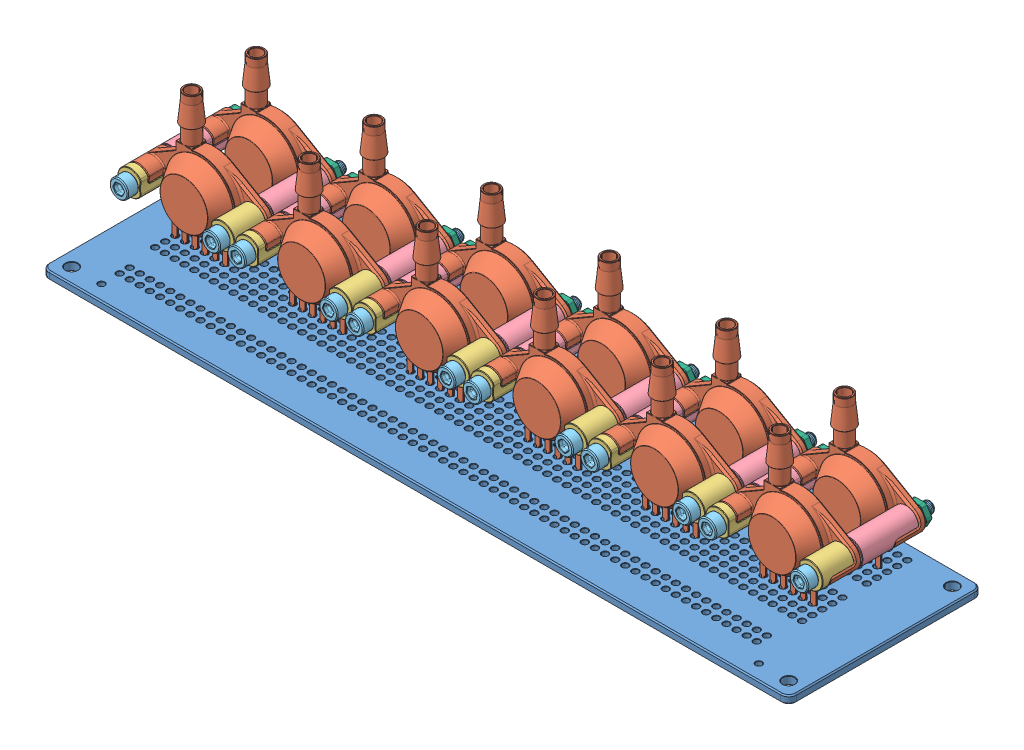
SolidWorks assembly AARL_Puppy_18_03_02_000, configuration Default. Lengths in mm.
Overall size (187.96 37.75 48.78).
61 component instances, 6 part files, 168 mates.
Components (placement in the parent):
- AARL_Puppy_18_03_01_006-1: AARL_Puppy_18_03_01_006 [Default] at origin size (187.96 2 48.78)
- AARL_Puppy_18_03_01_002-MPX5700GP-1: AARL_Puppy_18_03_01_002-MPX5700GP [Default] at (-77.5527 13 4.34) size (29.5 37.75 8.49)
- AARL_Puppy_18_03_01_002-MPX5700GP-2: AARL_Puppy_18_03_01_002-MPX5700GP [Default] at (-47.9676 13 4.34) size (29.5 37.75 8.49)
- AARL_Puppy_18_03_01_002-MPX5700GP-3: AARL_Puppy_18_03_01_002-MPX5700GP [Default] at (-18.3825 13 4.34) size (29.5 37.75 8.49)
- AARL_Puppy_18_03_01_002-MPX5700GP-4: AARL_Puppy_18_03_01_002-MPX5700GP [Default] at (11.2026 13 4.34) size (29.5 37.75 8.49)
- AARL_Puppy_18_03_01_002-MPX5700GP-5: AARL_Puppy_18_03_01_002-MPX5700GP [Default] at (40.7877 13 4.34) size (29.5 37.75 8.49)
- AARL_Puppy_18_03_01_002-MPX5700GP-6: AARL_Puppy_18_03_01_002-MPX5700GP [Default] at (70.3728 13 4.34) size (29.5 37.75 8.49)
- AARL_Puppy_18_03_01_002-MPX5700GP-7: AARL_Puppy_18_03_01_002-MPX5700GP [Default] at (-77.5527 13 -11.94) size (29.5 37.75 8.49)
- AARL_Puppy_18_03_01_002-MPX5700GP-8: AARL_Puppy_18_03_01_002-MPX5700GP [Default] at (-47.9676 13 -11.94) size (29.5 37.75 8.49)
- AARL_Puppy_18_03_01_002-MPX5700GP-9: AARL_Puppy_18_03_01_002-MPX5700GP [Default] at (-18.3825 13 -11.94) size (29.5 37.75 8.49)
- AARL_Puppy_18_03_01_002-MPX5700GP-10: AARL_Puppy_18_03_01_002-MPX5700GP [Default] at (11.2026 13 -11.94) size (29.5 37.75 8.49)
- AARL_Puppy_18_03_01_002-MPX5700GP-11: AARL_Puppy_18_03_01_002-MPX5700GP [Default] at (40.7877 13 -11.94) size (29.5 37.75 8.49)
- AARL_Puppy_18_03_01_002-MPX5700GP-12: AARL_Puppy_18_03_01_002-MPX5700GP [Default] at (70.3728 13 -11.94) size (29.5 37.75 8.49)
- AARL_Puppy_18_03_01_007-1: AARL_Puppy_18_03_01_007 [Default] at (-89.1077 13 14.3385) x (0 1 0) z (-1 0 0) size (6.35 8 5.84)
- AARL_Puppy_18_03_01_007-2: AARL_Puppy_18_03_01_007 [Default] at (-65.9977 13 14.3385) x (0 -1 0) z (1 0 0) size (6.35 8 5.84)
- AARL_Puppy_18_03_01_007-3: AARL_Puppy_18_03_01_007 [Default] at (-59.5226 13 14.3385) x (0 1 0) z (-1 0 0) size (6.35 8 5.84)
- AARL_Puppy_18_03_01_007-4: AARL_Puppy_18_03_01_007 [Default] at (-36.4126 13 14.3385) x (0 -1 0) z (1 0 0) size (6.35 8 5.84)
- AARL_Puppy_18_03_01_007-5: AARL_Puppy_18_03_01_007 [Default] at (-29.9375 13 14.3385) x (0 1 0) z (-1 0 0) size (6.35 8 5.84)
- AARL_Puppy_18_03_01_007-6: AARL_Puppy_18_03_01_007 [Default] at (-6.8275 13 14.3385) x (0 -1 0) z (1 0 0) size (6.35 8 5.84)
- AARL_Puppy_18_03_01_007-7: AARL_Puppy_18_03_01_007 [Default] at (-0.3524 13 14.3385) x (0 1 0) z (-1 0 0) size (6.35 8 5.84)
- AARL_Puppy_18_03_01_007-8: AARL_Puppy_18_03_01_007 [Default] at (22.7576 13 14.3385) x (0 -1 0) z (1 0 0) size (6.35 8 5.84)
- AARL_Puppy_18_03_01_007-9: AARL_Puppy_18_03_01_007 [Default] at (29.2327 13 14.3385) x (0 1 0) z (-1 0 0) size (6.35 8 5.84)
- AARL_Puppy_18_03_01_007-10: AARL_Puppy_18_03_01_007 [Default] at (52.3427 13 14.3385) x (0 -1 0) z (1 0 0) size (6.35 8 5.84)
- AARL_Puppy_18_03_01_007-11: AARL_Puppy_18_03_01_007 [Default] at (58.8178 13 14.3385) x (0 1 0) z (-1 0 0) size (6.35 8 5.84)
- AARL_Puppy_18_03_01_007-12: AARL_Puppy_18_03_01_007 [Default] at (81.9278 13 14.3385) x (0 -1 0) z (1 0 0) size (6.35 8 5.84)
- AARL_Puppy_18_03_01_008-1: AARL_Puppy_18_03_01_008 [Default] at (-89.1077 13 4.3399) x (0 1 0) z (-1 0 0) size (6.35 14.28 5.84)
- AARL_Puppy_18_03_01_008-2: AARL_Puppy_18_03_01_008 [Default] at (-65.9977 13 4.3399) x (0 -1 0) z (1 0 0) size (6.35 14.28 5.84)
- AARL_Puppy_18_03_01_008-3: AARL_Puppy_18_03_01_008 [Default] at (-59.5226 13 4.3399) x (0 1 0) z (-1 0 0) size (6.35 14.28 5.84)
- AARL_Puppy_18_03_01_008-4: AARL_Puppy_18_03_01_008 [Default] at (-36.4126 13 4.3399) x (0 -1 0) z (1 0 0) size (6.35 14.28 5.84)
- AARL_Puppy_18_03_01_008-5: AARL_Puppy_18_03_01_008 [Default] at (-29.9375 13 4.3399) x (0 1 0) z (-1 0 0) size (6.35 14.28 5.84)
- AARL_Puppy_18_03_01_008-6: AARL_Puppy_18_03_01_008 [Default] at (-6.8275 13 4.3399) x (0 -1 0) z (1 0 0) size (6.35 14.28 5.84)
- AARL_Puppy_18_03_01_008-7: AARL_Puppy_18_03_01_008 [Default] at (-0.3524 13 4.3399) x (0 1 0) z (-1 0 0) size (6.35 14.28 5.84)
- AARL_Puppy_18_03_01_008-8: AARL_Puppy_18_03_01_008 [Default] at (22.7576 13 4.3399) x (0 -1 0) z (1 0 0) size (6.35 14.28 5.84)
- AARL_Puppy_18_03_01_008-9: AARL_Puppy_18_03_01_008 [Default] at (29.2327 13 4.3399) x (0 1 0) z (-1 0 0) size (6.35 14.28 5.84)
- AARL_Puppy_18_03_01_008-10: AARL_Puppy_18_03_01_008 [Default] at (52.3427 13 4.3399) x (0 -1 0) z (1 0 0) size (6.35 14.28 5.84)
- AARL_Puppy_18_03_01_008-11: AARL_Puppy_18_03_01_008 [Default] at (58.8178 13 4.3399) x (0 1 0) z (-1 0 0) size (6.35 14.28 5.84)
- AARL_Puppy_18_03_01_008-12: AARL_Puppy_18_03_01_008 [Default] at (81.9278 13 4.3399) x (0 -1 0) z (1 0 0) size (6.35 14.28 5.84)
- AARL_Puppy_18_04_01_010-1: AARL_Puppy_18_04_01_010 [Default] at (-89.1077 13 17.1833) x (0.827068 0.562102 0) z (-0.562102 0.827068 0) size (4.65 33.19 4.65)
- AARL_Puppy_18_04_01_010-2: AARL_Puppy_18_04_01_010 [Default] at (-65.9977 13 17.1833) x (0.827068 0.562102 0) z (-0.562102 0.827068 0) size (4.65 33.19 4.65)
- AARL_Puppy_18_04_01_010-3: AARL_Puppy_18_04_01_010 [Default] at (-59.5226 13 17.1833) x (0.567888 -0.823106 0) z (0.823106 0.567888 0) size (4.65 33.19 4.65)
- AARL_Puppy_18_04_01_010-4: AARL_Puppy_18_04_01_010 [Default] at (-36.4126 13 17.1833) x (0.934298 -0.356493 0) z (0.356493 0.934298 0) size (4.65 33.19 4.65)
- AARL_Puppy_18_04_01_010-5: AARL_Puppy_18_04_01_010 [Default] at (-29.9375 13 17.1833) x (0.934298 -0.356493 0) z (0.356493 0.934298 0) size (4.65 33.19 4.65)
- AARL_Puppy_18_04_01_010-6: AARL_Puppy_18_04_01_010 [Default] at (-6.8275 13 17.1833) x (0.934298 -0.356493 0) z (0.356493 0.934298 0) size (4.65 33.19 4.65)
- AARL_Puppy_18_04_01_010-7: AARL_Puppy_18_04_01_010 [Default] at (-0.3524 13 17.1833) x (0.422012 -0.90659 0) z (0.90659 0.422012 0) size (4.65 33.19 4.65)
- AARL_Puppy_18_04_01_010-8: AARL_Puppy_18_04_01_010 [Default] at (22.7576 13 17.1833) x (0.687558 -0.726129 0) z (0.726129 0.687558 0) size (4.65 33.19 4.65)
- AARL_Puppy_18_04_01_010-9: AARL_Puppy_18_04_01_010 [Default] at (29.2327 13 17.1833) x (-0.114467 -0.993427 0) z (0.993427 -0.114467 0) size (4.65 33.19 4.65)
- AARL_Puppy_18_04_01_010-10: AARL_Puppy_18_04_01_010 [Default] at (52.3427 13 17.1833) x (-0.114467 -0.993427 0) z (0.993427 -0.114467 0) size (4.65 33.19 4.65)
- AARL_Puppy_18_04_01_010-11: AARL_Puppy_18_04_01_010 [Default] at (58.8178 13 17.1833) x (-0.684268 -0.729231 0) z (0.729231 -0.684268 0) size (4.65 33.19 4.65)
- AARL_Puppy_18_04_01_010-12: AARL_Puppy_18_04_01_010 [Default] at (81.9278 13 17.1833) x (-0.684268 -0.729231 0) z (0.729231 -0.684268 0) size (4.65 33.19 4.65)
- AARL_Puppy_18_04_07_002-1: AARL_Puppy_18_04_07_002 [Default] at (-89.1077 13 -12.7338) x (1 0 0) z (0 -1 0) size (5.77 1.59 5.21)
- AARL_Puppy_18_04_07_002-2: AARL_Puppy_18_04_07_002 [Default] at (-65.9977 13 -12.7338) x (1 0 0) z (0 -1 0) size (5.77 1.59 5.21)
- AARL_Puppy_18_04_07_002-3: AARL_Puppy_18_04_07_002 [Default] at (-59.5226 13 -12.7338) x (1 0 0) z (0 -1 0) size (5.77 1.59 5.21)
- AARL_Puppy_18_04_07_002-4: AARL_Puppy_18_04_07_002 [Default] at (-36.4126 13 -12.7338) x (1 0 0) z (0 -1 0) size (5.77 1.59 5.21)
- AARL_Puppy_18_04_07_002-5: AARL_Puppy_18_04_07_002 [Default] at (-29.9375 13 -12.7338) x (1 0 0) z (0 -1 0) size (5.77 1.59 5.21)
- AARL_Puppy_18_04_07_002-6: AARL_Puppy_18_04_07_002 [Default] at (-6.8275 13 -12.7338) x (1 0 0) z (0 -1 0) size (5.77 1.59 5.21)
- AARL_Puppy_18_04_07_002-7: AARL_Puppy_18_04_07_002 [Default] at (-0.3524 13 -12.7338) x (0.513984 -0.8578 0) z (-0.8578 -0.513984 0) size (5.77 1.59 5.21)
- AARL_Puppy_18_04_07_002-8: AARL_Puppy_18_04_07_002 [Default] at (22.7576 13 -12.7338) x (0.513984 -0.8578 0) z (-0.8578 -0.513984 0) size (5.77 1.59 5.21)
- AARL_Puppy_18_04_07_002-9: AARL_Puppy_18_04_07_002 [Default] at (29.2327 13 -12.7338) x (0.513984 -0.8578 0) z (-0.8578 -0.513984 0) size (5.77 1.59 5.21)
- AARL_Puppy_18_04_07_002-10: AARL_Puppy_18_04_07_002 [Default] at (52.3427 13 -12.7338) x (0.513984 -0.8578 0) z (-0.8578 -0.513984 0) size (5.77 1.59 5.21)
- AARL_Puppy_18_04_07_002-11: AARL_Puppy_18_04_07_002 [Default] at (58.8178 13 -12.7338) x (0.513984 -0.8578 0) z (-0.8578 -0.513984 0) size (5.77 1.59 5.21)
- AARL_Puppy_18_04_07_002-12: AARL_Puppy_18_04_07_002 [Default] at (81.9278 13 -12.7338) x (0.513984 -0.8578 0) z (-0.8578 -0.513984 0) size (5.77 1.59 5.21)
Mates (geometry in assembly coordinates):
- Width1: width: plane of AARL_Puppy_18_03_01_002-MPX5700GP-1 through (-83.5277 -4.75 7.94) normal (1 0 0); plane of AARL_Puppy_18_03_01_002-MPX5700GP-1 through (-84.2777 -4.75 7.94) normal (-1 0 0); cylinder of AARL_Puppy_18_03_01_006-1 through (-83.9027 -1 8.14) axis (0 1 0) radius 0.75
- Width2: width: plane of AARL_Puppy_18_03_01_002-MPX5700GP-1 through (-89.1077 13 8.34) normal (0 0 1); plane of AARL_Puppy_18_03_01_002-MPX5700GP-1 through (-83.1527 33.001 7.94) normal (0 0 -1); cylinder of AARL_Puppy_18_03_01_006-1 through (-83.9027 -1 8.14) axis (0 1 0) radius 0.75
- Width3: width: plane of AARL_Puppy_18_03_01_002-MPX5700GP-1 through (-89.1077 13 8.34) normal (0 0 1); plane of AARL_Puppy_18_03_01_002-MPX5700GP-1 through (-70.4527 33.001 7.94) normal (0 0 -1); cylinder of AARL_Puppy_18_03_01_006-1 through (-71.5756 -1 8.14) axis (0 1 0) radius 0.75
- Coincident1: coincident anti-aligned: plane of AARL_Puppy_18_03_01_006-1 through (0 1 0) normal (0 1 0); plane of AARL_Puppy_18_03_01_002-MPX5700GP-1 through (-77.5527 1 4.34) normal (0 -1 0)
- Width4: width: plane of AARL_Puppy_18_03_01_002-MPX5700GP-2 through (-59.5226 13 8.34) normal (0 0 1); plane of AARL_Puppy_18_03_01_002-MPX5700GP-2 through (-53.5676 33.001 7.94) normal (0 0 -1); cylinder of AARL_Puppy_18_03_01_006-1 through (-54.3176 -1 8.14) axis (0 1 0) radius 0.75
- Width5: width: plane of AARL_Puppy_18_03_01_002-MPX5700GP-2 through (-40.8676 33.001 7.94) normal (0 0 -1); plane of AARL_Puppy_18_03_01_002-MPX5700GP-2 through (-59.5226 13 8.34) normal (0 0 1); cylinder of AARL_Puppy_18_03_01_006-1 through (-41.9905 -1 8.14) axis (0 1 0) radius 0.75
- Width6: width: plane of AARL_Puppy_18_03_01_002-MPX5700GP-2 through (-54.6926 -4.75 7.94) normal (-1 0 0); plane of AARL_Puppy_18_03_01_002-MPX5700GP-2 through (-53.9426 -4.75 7.94) normal (1 0 0); cylinder of AARL_Puppy_18_03_01_006-1 through (-54.3176 -1 8.14) axis (0 1 0) radius 0.75
- Coincident2: coincident anti-aligned: plane of AARL_Puppy_18_03_01_006-1 through (0 1 0) normal (0 1 0); plane of AARL_Puppy_18_03_01_002-MPX5700GP-2 through (-47.9676 1 4.34) normal (0 -1 0)
- Width7: width: plane of AARL_Puppy_18_03_01_002-MPX5700GP-3 through (-23.9825 33.001 7.94) normal (0 0 -1); plane of AARL_Puppy_18_03_01_002-MPX5700GP-3 through (-29.9375 13 8.34) normal (0 0 1); cylinder of AARL_Puppy_18_03_01_006-1 through (-24.7325 -1 8.14) axis (0 1 0) radius 0.75
- Width8: width: plane of AARL_Puppy_18_03_01_002-MPX5700GP-3 through (-11.2825 33.001 7.94) normal (0 0 -1); plane of AARL_Puppy_18_03_01_002-MPX5700GP-3 through (-29.9375 13 8.34) normal (0 0 1); cylinder of AARL_Puppy_18_03_01_006-1 through (-12.4054 -1 8.14) axis (0 1 0) radius 0.75
- Width9: width: plane of AARL_Puppy_18_03_01_002-MPX5700GP-3 through (-24.3575 -4.75 7.94) normal (1 0 0); plane of AARL_Puppy_18_03_01_002-MPX5700GP-3 through (-25.1075 -4.75 7.94) normal (-1 0 0); cylinder of AARL_Puppy_18_03_01_006-1 through (-24.7325 -1 8.14) axis (0 1 0) radius 0.75
- Coincident3: coincident anti-aligned: plane of AARL_Puppy_18_03_01_006-1 through (0 1 0) normal (0 1 0); plane of AARL_Puppy_18_03_01_002-MPX5700GP-3 through (-18.3825 1 4.34) normal (0 -1 0)
- Width10: width: plane of AARL_Puppy_18_03_01_002-MPX5700GP-4 through (5.6026 33.001 7.94) normal (0 0 -1); plane of AARL_Puppy_18_03_01_002-MPX5700GP-4 through (-0.3524 13 8.34) normal (0 0 1); cylinder of AARL_Puppy_18_03_01_006-1 through (4.8526 -1 8.14) axis (0 1 0) radius 0.75
- Width11: width: plane of AARL_Puppy_18_03_01_002-MPX5700GP-4 through (4.4776 -4.75 7.94) normal (-1 0 0); plane of AARL_Puppy_18_03_01_002-MPX5700GP-4 through (5.2276 -4.75 7.94) normal (1 0 0); cylinder of AARL_Puppy_18_03_01_006-1 through (4.8526 -1 8.14) axis (0 1 0) radius 0.75
- Width12: width: plane of AARL_Puppy_18_03_01_002-MPX5700GP-4 through (18.3026 33.001 7.94) normal (0 0 -1); plane of AARL_Puppy_18_03_01_002-MPX5700GP-4 through (-0.3524 13 8.34) normal (0 0 1); cylinder of AARL_Puppy_18_03_01_006-1 through (17.1797 -1 8.14) axis (0 1 0) radius 0.75
- Coincident4: coincident anti-aligned: plane of AARL_Puppy_18_03_01_006-1 through (0 1 0) normal (0 1 0); plane of AARL_Puppy_18_03_01_002-MPX5700GP-4 through (11.2026 1 4.34) normal (0 -1 0)
- Width13: width: plane of AARL_Puppy_18_03_01_002-MPX5700GP-5 through (35.1877 33.001 7.94) normal (0 0 -1); plane of AARL_Puppy_18_03_01_002-MPX5700GP-5 through (29.2327 13 8.34) normal (0 0 1); cylinder of AARL_Puppy_18_03_01_006-1 through (34.4377 -1 8.14) axis (0 1 0) radius 0.75
- Width14: width: plane of AARL_Puppy_18_03_01_002-MPX5700GP-5 through (34.0627 -4.75 7.94) normal (-1 0 0); plane of AARL_Puppy_18_03_01_002-MPX5700GP-5 through (34.8127 -4.75 7.94) normal (1 0 0); cylinder of AARL_Puppy_18_03_01_006-1 through (34.4377 -1 8.14) axis (0 1 0) radius 0.75
- Width15: width: plane of AARL_Puppy_18_03_01_002-MPX5700GP-5 through (47.8877 33.001 7.94) normal (0 0 -1); plane of AARL_Puppy_18_03_01_002-MPX5700GP-5 through (29.2327 13 8.34) normal (0 0 1); cylinder of AARL_Puppy_18_03_01_006-1 through (46.7648 -1 8.14) axis (0 1 0) radius 0.75
- Coincident5: coincident anti-aligned: plane of AARL_Puppy_18_03_01_006-1 through (0 1 0) normal (0 1 0); plane of AARL_Puppy_18_03_01_002-MPX5700GP-5 through (40.7877 1 4.34) normal (0 -1 0)
- Width16: width: plane of AARL_Puppy_18_03_01_002-MPX5700GP-6 through (64.3978 -4.75 7.94) normal (1 0 0); plane of AARL_Puppy_18_03_01_002-MPX5700GP-6 through (63.6478 -4.75 7.94) normal (-1 0 0); cylinder of AARL_Puppy_18_03_01_006-1 through (64.0228 -1 8.14) axis (0 1 0) radius 0.75
- Width17: width: plane of AARL_Puppy_18_03_01_002-MPX5700GP-6 through (58.8178 13 8.34) normal (0 0 1); plane of AARL_Puppy_18_03_01_002-MPX5700GP-6 through (64.7728 33.001 7.94) normal (0 0 -1); cylinder of AARL_Puppy_18_03_01_006-1 through (64.0228 -1 8.14) axis (0 1 0) radius 0.75
- Width18: width: plane of AARL_Puppy_18_03_01_002-MPX5700GP-6 through (58.8178 13 8.34) normal (0 0 1); plane of AARL_Puppy_18_03_01_002-MPX5700GP-6 through (77.4728 33.001 7.94) normal (0 0 -1); cylinder of AARL_Puppy_18_03_01_006-1 through (76.3499 -1 8.14) axis (0 1 0) radius 0.75
- Coincident6: coincident anti-aligned: plane of AARL_Puppy_18_03_01_006-1 through (0 1 0) normal (0 1 0); plane of AARL_Puppy_18_03_01_002-MPX5700GP-6 through (70.3728 1 4.34) normal (0 -1 0)
- Width19: width: plane of AARL_Puppy_18_03_01_002-MPX5700GP-7 through (-83.5277 -4.75 -8.34) normal (1 0 0); plane of AARL_Puppy_18_03_01_002-MPX5700GP-7 through (-84.2777 -4.75 -8.34) normal (-1 0 0); cylinder of AARL_Puppy_18_03_01_006-1 through (-83.9027 -1 -8.14) axis (0 1 0) radius 0.75
- Width20: width: plane of AARL_Puppy_18_03_01_002-MPX5700GP-7 through (-89.1077 13 -7.94) normal (0 0 1); plane of AARL_Puppy_18_03_01_002-MPX5700GP-7 through (-83.1527 33.001 -8.34) normal (0 0 -1); cylinder of AARL_Puppy_18_03_01_006-1 through (-83.9027 -1 -8.14) axis (0 1 0) radius 0.75
- Width21: width: plane of AARL_Puppy_18_03_01_002-MPX5700GP-7 through (-70.4527 33.001 -8.34) normal (0 0 -1); plane of AARL_Puppy_18_03_01_002-MPX5700GP-7 through (-89.1077 13 -7.94) normal (0 0 1); cylinder of AARL_Puppy_18_03_01_006-1 through (-71.5756 -1 -8.14) axis (0 1 0) radius 0.75
- Coincident7: coincident anti-aligned: plane of AARL_Puppy_18_03_01_006-1 through (0 1 0) normal (0 1 0); plane of AARL_Puppy_18_03_01_002-MPX5700GP-7 through (-77.5527 1 -11.94) normal (0 -1 0)
- Width22: width: plane of AARL_Puppy_18_03_01_002-MPX5700GP-8 through (-59.5226 13 -7.94) normal (0 0 1); plane of AARL_Puppy_18_03_01_002-MPX5700GP-8 through (-53.5676 33.001 -8.34) normal (0 0 -1); cylinder of AARL_Puppy_18_03_01_006-1 through (-51.8522 -1 -8.14) axis (0 1 0) radius 0.75
- Width23: width: plane of AARL_Puppy_18_03_01_002-MPX5700GP-8 through (-53.9426 -4.75 -8.34) normal (1 0 0); plane of AARL_Puppy_18_03_01_002-MPX5700GP-8 through (-54.6926 -4.75 -8.34) normal (-1 0 0); cylinder of AARL_Puppy_18_03_01_006-1 through (-54.3176 -1 -8.14) axis (0 1 0) radius 0.75
- Width24: width: plane of AARL_Puppy_18_03_01_002-MPX5700GP-8 through (-40.8676 33.001 -8.34) normal (0 0 -1); plane of AARL_Puppy_18_03_01_002-MPX5700GP-8 through (-59.5226 13 -7.94) normal (0 0 1); cylinder of AARL_Puppy_18_03_01_006-1 through (-41.9905 -1 -8.14) axis (0 1 0) radius 0.75
- Coincident8: coincident anti-aligned: plane of AARL_Puppy_18_03_01_006-1 through (0 1 0) normal (0 1 0); plane of AARL_Puppy_18_03_01_002-MPX5700GP-8 through (-47.9676 1 -11.94) normal (0 -1 0)
- Width25: width: plane of AARL_Puppy_18_03_01_002-MPX5700GP-9 through (-23.9825 33.001 -8.34) normal (0 0 -1); plane of AARL_Puppy_18_03_01_002-MPX5700GP-9 through (-29.9375 13 -7.94) normal (0 0 1); cylinder of AARL_Puppy_18_03_01_006-1 through (-24.7325 -1 -8.14) axis (0 1 0) radius 0.75
- Width26: width: plane of AARL_Puppy_18_03_01_002-MPX5700GP-9 through (-25.1075 -4.75 -8.34) normal (-1 0 0); plane of AARL_Puppy_18_03_01_002-MPX5700GP-9 through (-24.3575 -4.75 -8.34) normal (1 0 0); cylinder of AARL_Puppy_18_03_01_006-1 through (-24.7325 -1 -8.14) axis (0 1 0) radius 0.75
- Width27: width: plane of AARL_Puppy_18_03_01_002-MPX5700GP-9 through (-11.2825 33.001 -8.34) normal (0 0 -1); plane of AARL_Puppy_18_03_01_002-MPX5700GP-9 through (-29.9375 13 -7.94) normal (0 0 1); cylinder of AARL_Puppy_18_03_01_006-1 through (-12.4054 -1 -8.14) axis (0 1 0) radius 0.75
- Coincident9: coincident anti-aligned: plane of AARL_Puppy_18_03_01_006-1 through (0 1 0) normal (0 1 0); plane of AARL_Puppy_18_03_01_002-MPX5700GP-9 through (-18.3825 1 -11.94) normal (0 -1 0)
- Width28: width: plane of AARL_Puppy_18_03_01_002-MPX5700GP-10 through (-0.3524 13 -7.94) normal (0 0 1); plane of AARL_Puppy_18_03_01_002-MPX5700GP-10 through (5.6026 33.001 -8.34) normal (0 0 -1); cylinder of AARL_Puppy_18_03_01_006-1 through (4.8526 -1 -8.14) axis (0 1 0) radius 0.75
- Width29: width: plane of AARL_Puppy_18_03_01_002-MPX5700GP-10 through (5.2276 -4.75 -8.34) normal (1 0 0); plane of AARL_Puppy_18_03_01_002-MPX5700GP-10 through (4.4776 -4.75 -8.34) normal (-1 0 0); cylinder of AARL_Puppy_18_03_01_006-1 through (4.8526 -1 -8.14) axis (0 1 0) radius 0.75
- Width30: width: plane of AARL_Puppy_18_03_01_002-MPX5700GP-10 through (18.3026 33.001 -8.34) normal (0 0 -1); plane of AARL_Puppy_18_03_01_002-MPX5700GP-10 through (-0.3524 13 -7.94) normal (0 0 1); cylinder of AARL_Puppy_18_03_01_006-1 through (17.1797 -1 -8.14) axis (0 1 0) radius 0.75
- Coincident10: coincident anti-aligned: plane of AARL_Puppy_18_03_01_006-1 through (0 1 0) normal (0 1 0); plane of AARL_Puppy_18_03_01_002-MPX5700GP-10 through (11.2026 1 -11.94) normal (0 -1 0)
- Width31: width: plane of AARL_Puppy_18_03_01_002-MPX5700GP-11 through (35.1877 33.001 -8.34) normal (0 0 -1); plane of AARL_Puppy_18_03_01_002-MPX5700GP-11 through (29.2327 13 -7.94) normal (0 0 1); cylinder of AARL_Puppy_18_03_01_006-1 through (34.4377 -1 -8.14) axis (0 1 0) radius 0.75
- Width32: width: plane of AARL_Puppy_18_03_01_002-MPX5700GP-11 through (34.8127 -4.75 -8.34) normal (1 0 0); plane of AARL_Puppy_18_03_01_002-MPX5700GP-11 through (34.0627 -4.75 -8.34) normal (-1 0 0); cylinder of AARL_Puppy_18_03_01_006-1 through (34.4377 -1 -8.14) axis (0 1 0) radius 0.75
- Width33: width: plane of AARL_Puppy_18_03_01_002-MPX5700GP-11 through (47.8877 33.001 -8.34) normal (0 0 -1); plane of AARL_Puppy_18_03_01_002-MPX5700GP-11 through (29.2327 13 -7.94) normal (0 0 1); cylinder of AARL_Puppy_18_03_01_006-1 through (46.7648 -1 -8.14) axis (0 1 0) radius 0.75
- Coincident11: coincident anti-aligned: plane of AARL_Puppy_18_03_01_006-1 through (0 1 0) normal (0 1 0); plane of AARL_Puppy_18_03_01_002-MPX5700GP-11 through (40.7877 1 -11.94) normal (0 -1 0)
- Width34: width: plane of AARL_Puppy_18_03_01_002-MPX5700GP-12 through (64.7728 33.001 -8.34) normal (0 0 -1); plane of AARL_Puppy_18_03_01_002-MPX5700GP-12 through (58.8178 13 -7.94) normal (0 0 1); cylinder of AARL_Puppy_18_03_01_006-1 through (64.0228 -1 -8.14) axis (0 1 0) radius 0.75
- Width35: width: plane of AARL_Puppy_18_03_01_002-MPX5700GP-12 through (63.6478 -4.75 -8.34) normal (-1 0 0); plane of AARL_Puppy_18_03_01_002-MPX5700GP-12 through (64.3978 -4.75 -8.34) normal (1 0 0); cylinder of AARL_Puppy_18_03_01_006-1 through (64.0228 -1 -8.14) axis (0 1 0) radius 0.75
- Width36: width: plane of AARL_Puppy_18_03_01_002-MPX5700GP-12 through (77.4728 33.001 -8.34) normal (0 0 -1); plane of AARL_Puppy_18_03_01_002-MPX5700GP-12 through (58.8178 13 -7.94) normal (0 0 1); cylinder of AARL_Puppy_18_03_01_006-1 through (76.3499 -1 -8.14) axis (0 1 0) radius 0.75
- Coincident12: coincident anti-aligned: plane of AARL_Puppy_18_03_01_006-1 through (0 1 0) normal (0 1 0); plane of AARL_Puppy_18_03_01_002-MPX5700GP-12 through (70.3728 1 -11.94) normal (0 -1 0)
- Concentric1: concentric aligned: cylinder of AARL_Puppy_18_03_01_002-MPX5700GP-1 through (-89.1077 13 12.34) axis (0 0 -1) radius 2; cylinder of AARL_Puppy_18_03_01_007-1 through (-89.1077 13 12.4775) axis (0 0 -1) radius 1.9844
- Coincident13: coincident anti-aligned: plane of AARL_Puppy_18_03_01_002-MPX5700GP-1 through (-92.3027 13 -0.3777) normal (0 -1 0); plane of AARL_Puppy_18_03_01_007-1 through (-89.1077 13 6.34) normal (0 1 0)
- Coincident14: coincident anti-aligned: plane of AARL_Puppy_18_03_01_002-MPX5700GP-1 through (-77.5527 13 6.34) normal (0 0 1); plane of AARL_Puppy_18_03_01_007-1 through (-89.1077 16.175 6.34) normal (0 0 -1)
- Concentric2: concentric aligned: cylinder of AARL_Puppy_18_03_01_002-MPX5700GP-1 through (-65.9977 13 12.34) axis (0 0 -1) radius 2; cylinder of AARL_Puppy_18_03_01_007-2 through (-65.9977 13 12.4775) axis (0 0 -1) radius 1.9844
- Coincident15: coincident anti-aligned: plane of AARL_Puppy_18_03_01_002-MPX5700GP-1 through (-62.8027 13 -0.3777) normal (0 1 0); plane of AARL_Puppy_18_03_01_007-2 through (-65.9977 13 6.34) normal (0 -1 0)
- Coincident16: coincident anti-aligned: plane of AARL_Puppy_18_03_01_002-MPX5700GP-1 through (-65.9977 13 6.34) normal (0 0 1); plane of AARL_Puppy_18_03_01_007-2 through (-65.9977 9.825 6.34) normal (0 0 -1)
- Concentric3: concentric aligned: cylinder of AARL_Puppy_18_03_01_002-MPX5700GP-2 through (-59.5226 13 12.34) axis (0 0 -1) radius 2; cylinder of AARL_Puppy_18_03_01_007-3 through (-59.5226 13 12.4775) axis (0 0 -1) radius 1.9844
- Coincident17: coincident anti-aligned: plane of AARL_Puppy_18_03_01_002-MPX5700GP-2 through (-62.7176 13 -0.3777) normal (0 -1 0); plane of AARL_Puppy_18_03_01_007-3 through (-59.5226 13 6.34) normal (0 1 0)
- Coincident18: coincident anti-aligned: plane of AARL_Puppy_18_03_01_002-MPX5700GP-2 through (-47.9676 13 6.34) normal (0 0 1); plane of AARL_Puppy_18_03_01_007-3 through (-59.5226 16.175 6.34) normal (0 0 -1)
- Concentric4: concentric aligned: cylinder of AARL_Puppy_18_03_01_002-MPX5700GP-2 through (-36.4126 13 12.34) axis (0 0 -1) radius 2; cylinder of AARL_Puppy_18_03_01_007-4 through (-36.4126 13 12.4775) axis (0 0 -1) radius 1.9844
- Coincident19: coincident anti-aligned: plane of AARL_Puppy_18_03_01_002-MPX5700GP-2 through (-33.2176 13 -0.3777) normal (0 1 0); plane of AARL_Puppy_18_03_01_007-4 through (-36.4126 13 6.34) normal (0 -1 0)
- Coincident20: coincident anti-aligned: plane of AARL_Puppy_18_03_01_002-MPX5700GP-2 through (-36.4126 13 6.34) normal (0 0 1); plane of AARL_Puppy_18_03_01_007-4 through (-36.4126 9.825 6.34) normal (0 0 -1)
- Concentric5: concentric aligned: cylinder of AARL_Puppy_18_03_01_002-MPX5700GP-3 through (-29.9375 13 12.34) axis (0 0 -1) radius 2; cylinder of AARL_Puppy_18_03_01_007-5 through (-29.9375 13 12.4775) axis (0 0 -1) radius 1.9844
- Coincident21: coincident anti-aligned: plane of AARL_Puppy_18_03_01_002-MPX5700GP-3 through (-33.1325 13 -0.3777) normal (0 -1 0); plane of AARL_Puppy_18_03_01_007-5 through (-29.9375 13 6.34) normal (0 1 0)
- Coincident22: coincident anti-aligned: plane of AARL_Puppy_18_03_01_002-MPX5700GP-3 through (-18.3825 13 6.34) normal (0 0 1); plane of AARL_Puppy_18_03_01_007-5 through (-29.9375 16.175 6.34) normal (0 0 -1)
- Concentric6: concentric aligned: cylinder of AARL_Puppy_18_03_01_002-MPX5700GP-3 through (-6.8275 13 12.34) axis (0 0 -1) radius 2; cylinder of AARL_Puppy_18_03_01_007-6 through (-6.8275 13 12.4775) axis (0 0 -1) radius 1.9844
- Coincident23: coincident anti-aligned: plane of AARL_Puppy_18_03_01_002-MPX5700GP-3 through (-3.6325 13 -0.3777) normal (0 1 0); plane of AARL_Puppy_18_03_01_007-6 through (-6.8275 13 6.34) normal (0 -1 0)
- Coincident24: coincident anti-aligned: plane of AARL_Puppy_18_03_01_002-MPX5700GP-3 through (-6.8275 13 6.34) normal (0 0 1); plane of AARL_Puppy_18_03_01_007-6 through (-6.8275 9.825 6.34) normal (0 0 -1)
- Concentric7: concentric aligned: cylinder of AARL_Puppy_18_03_01_002-MPX5700GP-4 through (-0.3524 13 12.34) axis (0 0 -1) radius 2; cylinder of AARL_Puppy_18_03_01_007-7 through (-0.3524 13 12.4775) axis (0 0 -1) radius 1.9844
- Coincident25: coincident anti-aligned: plane of AARL_Puppy_18_03_01_002-MPX5700GP-4 through (-3.5474 13 -0.3777) normal (0 -1 0); plane of AARL_Puppy_18_03_01_007-7 through (-0.3524 13 6.34) normal (0 1 0)
- Coincident26: coincident anti-aligned: plane of AARL_Puppy_18_03_01_002-MPX5700GP-4 through (11.2026 13 6.34) normal (0 0 1); plane of AARL_Puppy_18_03_01_007-7 through (-0.3524 16.175 6.34) normal (0 0 -1)
- Concentric8: concentric aligned: cylinder of AARL_Puppy_18_03_01_007-8 through (22.7576 13 12.4775) axis (0 0 -1) radius 1.9844; cylinder of AARL_Puppy_18_03_01_002-MPX5700GP-4 through (22.7576 13 12.34) axis (0 0 -1) radius 2
- Coincident27: coincident anti-aligned: plane of AARL_Puppy_18_03_01_002-MPX5700GP-4 through (25.9526 13 -0.3777) normal (0 1 0); plane of AARL_Puppy_18_03_01_007-8 through (22.7576 13 6.34) normal (0 -1 0)
- Coincident28: coincident anti-aligned: plane of AARL_Puppy_18_03_01_002-MPX5700GP-4 through (22.7576 13 6.34) normal (0 0 1); plane of AARL_Puppy_18_03_01_007-8 through (22.7576 9.825 6.34) normal (0 0 -1)
- Concentric9: concentric aligned: cylinder of AARL_Puppy_18_03_01_002-MPX5700GP-5 through (29.2327 13 12.34) axis (0 0 -1) radius 2; cylinder of AARL_Puppy_18_03_01_007-9 through (29.2327 13 12.4775) axis (0 0 -1) radius 1.9844
- Coincident29: coincident anti-aligned: plane of AARL_Puppy_18_03_01_002-MPX5700GP-5 through (26.0377 13 -0.3777) normal (0 -1 0); plane of AARL_Puppy_18_03_01_007-9 through (29.2327 13 6.34) normal (0 1 0)
- Coincident30: coincident anti-aligned: plane of AARL_Puppy_18_03_01_002-MPX5700GP-5 through (40.7877 13 6.34) normal (0 0 1); plane of AARL_Puppy_18_03_01_007-9 through (29.2327 16.175 6.34) normal (0 0 -1)
- Concentric10: concentric aligned: cylinder of AARL_Puppy_18_03_01_002-MPX5700GP-5 through (52.3427 13 12.34) axis (0 0 -1) radius 2; cylinder of AARL_Puppy_18_03_01_007-10 through (52.3427 13 12.4775) axis (0 0 -1) radius 1.9844
- Coincident31: coincident anti-aligned: plane of AARL_Puppy_18_03_01_002-MPX5700GP-5 through (55.5377 13 -0.3777) normal (0 1 0); plane of AARL_Puppy_18_03_01_007-10 through (52.3427 13 6.34) normal (0 -1 0)
- Coincident32: coincident anti-aligned: plane of AARL_Puppy_18_03_01_002-MPX5700GP-5 through (52.3427 13 6.34) normal (0 0 1); plane of AARL_Puppy_18_03_01_007-10 through (52.3427 9.825 6.34) normal (0 0 -1)
- Concentric11: concentric aligned: cylinder of AARL_Puppy_18_03_01_002-MPX5700GP-6 through (58.8178 13 12.34) axis (0 0 -1) radius 2; cylinder of AARL_Puppy_18_03_01_007-11 through (58.8178 13 12.4775) axis (0 0 -1) radius 1.9844
- Coincident33: coincident anti-aligned: plane of AARL_Puppy_18_03_01_002-MPX5700GP-6 through (55.6228 13 -0.3777) normal (0 -1 0); plane of AARL_Puppy_18_03_01_007-11 through (58.8178 13 6.34) normal (0 1 0)
- Coincident34: coincident anti-aligned: plane of AARL_Puppy_18_03_01_002-MPX5700GP-6 through (70.3728 13 6.34) normal (0 0 1); plane of AARL_Puppy_18_03_01_007-11 through (58.8178 16.175 6.34) normal (0 0 -1)
- Concentric12: concentric aligned: cylinder of AARL_Puppy_18_03_01_002-MPX5700GP-6 through (81.9278 13 12.34) axis (0 0 -1) radius 2; cylinder of AARL_Puppy_18_03_01_007-12 through (81.9278 13 12.4775) axis (0 0 -1) radius 1.9844
- Coincident35: coincident anti-aligned: plane of AARL_Puppy_18_03_01_002-MPX5700GP-6 through (85.1228 13 -0.3777) normal (0 1 0); plane of AARL_Puppy_18_03_01_007-12 through (81.9278 13 6.34) normal (0 -1 0)
- Coincident36: coincident anti-aligned: plane of AARL_Puppy_18_03_01_002-MPX5700GP-6 through (81.9278 13 6.34) normal (0 0 1); plane of AARL_Puppy_18_03_01_007-12 through (81.9278 9.825 6.34) normal (0 0 -1)
- Concentric13: concentric aligned: cylinder of AARL_Puppy_18_03_01_002-MPX5700GP-7 through (-89.1077 13 -3.94) axis (0 0 -1) radius 2; cylinder of AARL_Puppy_18_03_01_008-1 through (-89.1077 13 2.4789) axis (0 0 -1) radius 1.9844
- Coincident37: coincident anti-aligned: plane of AARL_Puppy_18_03_01_002-MPX5700GP-7 through (-92.3027 13 -16.6577) normal (0 -1 0); plane of AARL_Puppy_18_03_01_008-1 through (-89.1077 13 -3.9405) normal (0 1 0)
- Coincident38: coincident anti-aligned: plane of AARL_Puppy_18_03_01_002-MPX5700GP-7 through (-77.5527 13 -9.94) normal (0 0 1); plane of AARL_Puppy_18_03_01_008-1 through (-89.1077 16.175 -9.94) normal (0 0 -1)
- Concentric14: concentric aligned: cylinder of AARL_Puppy_18_03_01_002-MPX5700GP-7 through (-65.9977 13 -3.94) axis (0 0 -1) radius 2; cylinder of AARL_Puppy_18_03_01_008-2 through (-65.9977 13 2.4789) axis (0 0 -1) radius 1.9844
- Coincident39: coincident anti-aligned: plane of AARL_Puppy_18_03_01_002-MPX5700GP-7 through (-62.8027 13 -16.6577) normal (0 1 0); plane of AARL_Puppy_18_03_01_008-2 through (-65.9977 13 -3.9405) normal (0 -1 0)
- Coincident40: coincident anti-aligned: plane of AARL_Puppy_18_03_01_002-MPX5700GP-7 through (-65.9977 13 -9.94) normal (0 0 1); plane of AARL_Puppy_18_03_01_008-2 through (-65.9977 9.825 -9.94) normal (0 0 -1)
- Concentric15: concentric aligned: cylinder of AARL_Puppy_18_03_01_002-MPX5700GP-8 through (-59.5226 13 -3.94) axis (0 0 -1) radius 2; circle of AARL_Puppy_18_03_01_008-3
- Coincident41: coincident anti-aligned: plane of AARL_Puppy_18_03_01_002-MPX5700GP-8 through (-62.7176 13 -16.6577) normal (0 -1 0); plane of AARL_Puppy_18_03_01_008-3 through (-59.5226 13 -3.9405) normal (0 1 0)
- Coincident42: coincident anti-aligned: plane of AARL_Puppy_18_03_01_002-MPX5700GP-8 through (-47.9676 13 -9.94) normal (0 0 1); plane of AARL_Puppy_18_03_01_008-3 through (-59.5226 16.175 -9.94) normal (0 0 -1)
- Concentric16: concentric aligned: cylinder of AARL_Puppy_18_03_01_002-MPX5700GP-8 through (-36.4126 13 -3.94) axis (0 0 -1) radius 2; cylinder of AARL_Puppy_18_03_01_008-4 through (-36.4126 13 2.4789) axis (0 0 -1) radius 1.9844
- Coincident43: coincident anti-aligned: plane of AARL_Puppy_18_03_01_002-MPX5700GP-8 through (-33.2176 13 -16.6577) normal (0 1 0); plane of AARL_Puppy_18_03_01_008-4 through (-36.4126 13 -3.9405) normal (0 -1 0)
- Coincident44: coincident anti-aligned: plane of AARL_Puppy_18_03_01_002-MPX5700GP-8 through (-36.4126 13 -9.94) normal (0 0 1); plane of AARL_Puppy_18_03_01_008-4 through (-36.4126 9.825 -9.94) normal (0 0 -1)
- Concentric17: concentric aligned: cylinder of AARL_Puppy_18_03_01_002-MPX5700GP-9 through (-29.9375 13 -3.94) axis (0 0 -1) radius 2; cylinder of AARL_Puppy_18_03_01_008-5 through (-29.9375 13 2.4789) axis (0 0 -1) radius 1.9844
- Coincident45: coincident anti-aligned: plane of AARL_Puppy_18_03_01_002-MPX5700GP-9 through (-33.1325 13 -16.6577) normal (0 -1 0); plane of AARL_Puppy_18_03_01_008-5 through (-29.9375 13 -3.9405) normal (0 1 0)
- Coincident46: coincident anti-aligned: plane of AARL_Puppy_18_03_01_002-MPX5700GP-9 through (-18.3825 13 -9.94) normal (0 0 1); plane of AARL_Puppy_18_03_01_008-5 through (-29.9375 16.175 -9.94) normal (0 0 -1)
- Concentric18: concentric aligned: cylinder of AARL_Puppy_18_03_01_002-MPX5700GP-9 through (-6.8275 13 -3.94) axis (0 0 -1) radius 2; cylinder of AARL_Puppy_18_03_01_008-6 through (-6.8275 13 2.4789) axis (0 0 -1) radius 1.9844
- Coincident47: coincident anti-aligned: plane of AARL_Puppy_18_03_01_002-MPX5700GP-9 through (-3.6325 13 -16.6577) normal (0 1 0); plane of AARL_Puppy_18_03_01_008-6 through (-6.8275 13 -3.9405) normal (0 -1 0)
- Coincident48: coincident anti-aligned: plane of AARL_Puppy_18_03_01_002-MPX5700GP-9 through (-6.8275 13 -9.94) normal (0 0 1); plane of AARL_Puppy_18_03_01_008-6 through (-6.8275 9.825 -9.94) normal (0 0 -1)
- Concentric19: concentric aligned: cylinder of AARL_Puppy_18_03_01_002-MPX5700GP-10 through (-0.3524 13 -3.94) axis (0 0 -1) radius 2; cylinder of AARL_Puppy_18_03_01_008-7 through (-0.3524 13 2.4789) axis (0 0 -1) radius 1.9844
- Coincident49: coincident anti-aligned: plane of AARL_Puppy_18_03_01_002-MPX5700GP-10 through (-3.5474 13 -16.6577) normal (0 -1 0); plane of AARL_Puppy_18_03_01_008-7 through (-0.3524 13 -3.9405) normal (0 1 0)
- Coincident50: coincident anti-aligned: plane of AARL_Puppy_18_03_01_002-MPX5700GP-10 through (11.2026 13 -9.94) normal (0 0 1); plane of AARL_Puppy_18_03_01_008-7 through (-0.3524 16.175 -9.94) normal (0 0 -1)
- Concentric20: concentric aligned: cylinder of AARL_Puppy_18_03_01_002-MPX5700GP-10 through (22.7576 13 -3.94) axis (0 0 -1) radius 2; cylinder of AARL_Puppy_18_03_01_008-8 through (22.7576 13 2.4789) axis (0 0 -1) radius 1.9844
- Coincident51: coincident anti-aligned: plane of AARL_Puppy_18_03_01_002-MPX5700GP-10 through (25.9526 13 -16.6577) normal (0 1 0); plane of AARL_Puppy_18_03_01_008-8 through (22.7576 13 -3.9405) normal (0 -1 0)
- Coincident52: coincident anti-aligned: plane of AARL_Puppy_18_03_01_002-MPX5700GP-10 through (22.7576 13 -9.94) normal (0 0 1); plane of AARL_Puppy_18_03_01_008-8 through (22.7576 9.825 -9.94) normal (0 0 -1)
- Concentric21: concentric aligned: cylinder of AARL_Puppy_18_03_01_002-MPX5700GP-11 through (29.2327 13 -3.94) axis (0 0 -1) radius 2; cylinder of AARL_Puppy_18_03_01_008-9 through (29.2327 13 2.4789) axis (0 0 -1) radius 1.9844
- Coincident53: coincident anti-aligned: plane of AARL_Puppy_18_03_01_002-MPX5700GP-11 through (26.0377 13 -16.6577) normal (0 -1 0); plane of AARL_Puppy_18_03_01_008-9 through (29.2327 13 -3.9405) normal (0 1 0)
- Coincident54: coincident anti-aligned: plane of AARL_Puppy_18_03_01_002-MPX5700GP-11 through (40.7877 13 -9.94) normal (0 0 1); plane of AARL_Puppy_18_03_01_008-9 through (29.2327 16.175 -9.94) normal (0 0 -1)
- Concentric22: concentric aligned: cylinder of AARL_Puppy_18_03_01_002-MPX5700GP-11 through (52.3427 13 -3.94) axis (0 0 -1) radius 2; cylinder of AARL_Puppy_18_03_01_008-10 through (52.3427 13 2.4789) axis (0 0 -1) radius 1.9844
- Coincident55: coincident anti-aligned: plane of AARL_Puppy_18_03_01_002-MPX5700GP-11 through (55.5377 13 -16.6577) normal (0 1 0); plane of AARL_Puppy_18_03_01_008-10 through (52.3427 13 -3.9405) normal (0 -1 0)
- Coincident56: coincident anti-aligned: plane of AARL_Puppy_18_03_01_002-MPX5700GP-11 through (52.3427 13 -9.94) normal (0 0 1); plane of AARL_Puppy_18_03_01_008-10 through (52.3427 9.825 -9.94) normal (0 0 -1)
- Concentric23: concentric aligned: cylinder of AARL_Puppy_18_03_01_002-MPX5700GP-12 through (58.8178 13 -3.94) axis (0 0 -1) radius 2; cylinder of AARL_Puppy_18_03_01_008-11 through (58.8178 13 2.4789) axis (0 0 -1) radius 1.9844
- Coincident57: coincident anti-aligned: plane of AARL_Puppy_18_03_01_002-MPX5700GP-12 through (55.6228 13 -16.6577) normal (0 -1 0); plane of AARL_Puppy_18_03_01_008-11 through (58.8178 13 -3.9405) normal (0 1 0)
- Coincident58: coincident anti-aligned: plane of AARL_Puppy_18_03_01_002-MPX5700GP-12 through (70.3728 13 -9.94) normal (0 0 1); plane of AARL_Puppy_18_03_01_008-11 through (58.8178 16.175 -9.94) normal (0 0 -1)
- Concentric24: concentric aligned: cylinder of AARL_Puppy_18_03_01_002-MPX5700GP-12 through (81.9278 13 -3.94) axis (0 0 -1) radius 2; cylinder of AARL_Puppy_18_03_01_008-12 through (81.9278 13 2.4789) axis (0 0 -1) radius 1.9844
- Coincident59: coincident anti-aligned: plane of AARL_Puppy_18_03_01_002-MPX5700GP-12 through (85.1228 13 -16.6577) normal (0 1 0); plane of AARL_Puppy_18_03_01_008-12 through (81.9278 13 -3.9405) normal (0 -1 0)
- Coincident60: coincident anti-aligned: plane of AARL_Puppy_18_03_01_002-MPX5700GP-12 through (81.9278 13 -9.94) normal (0 0 1); plane of AARL_Puppy_18_03_01_008-12 through (81.9278 9.825 -9.94) normal (0 0 -1)
- Concentric25: concentric anti-aligned: cylinder of AARL_Puppy_18_03_01_007-1 through (-89.1077 13 12.4775) axis (0 0 -1) radius 1.9844; cylinder of AARL_Puppy_18_04_01_010-1 through (-89.1077 13 17.1833) axis (0 0 1) radius 1.4224
- Coincident61: coincident anti-aligned: plane of AARL_Puppy_18_03_01_007-1 through (-89.1077 14.9844 14.3385) normal (0 0 1); plane of AARL_Puppy_18_04_01_010-1 through (-87.9313 13.7995 14.3385) normal (0 0 -1)
- Concentric26: concentric anti-aligned: cylinder of AARL_Puppy_18_03_01_007-2 through (-65.9977 13 12.4775) axis (0 0 -1) radius 1.9844; cylinder of AARL_Puppy_18_04_01_010-2 through (-65.9977 13 17.1833) axis (0 0 1) radius 1.4224
- Coincident62: coincident anti-aligned: plane of AARL_Puppy_18_03_01_007-2 through (-65.9977 11.0156 14.3385) normal (0 0 1); plane of AARL_Puppy_18_04_01_010-2 through (-64.8213 13.7995 14.3385) normal (0 0 -1)
- Concentric27: concentric anti-aligned: cylinder of AARL_Puppy_18_04_01_010-3 through (-59.5226 13 17.1833) axis (0 0 1) radius 1.4224; cylinder of AARL_Puppy_18_03_01_007-3 through (-59.5226 13 12.4775) axis (0 0 -1) radius 1.9844
- Coincident63: coincident anti-aligned: plane of AARL_Puppy_18_03_01_007-3 through (-59.5226 14.9844 14.3385) normal (0 0 1); plane of AARL_Puppy_18_04_01_010-3 through (-58.7149 11.8292 14.3385) normal (0 0 -1)
- Concentric28: concentric anti-aligned: cylinder of AARL_Puppy_18_03_01_007-4 through (-36.4126 13 12.4775) axis (0 0 -1) radius 1.9844; cylinder of AARL_Puppy_18_04_01_010-4 through (-36.4126 13 17.1833) axis (0 0 1) radius 1.4224
- Coincident64: coincident anti-aligned: plane of AARL_Puppy_18_03_01_007-4 through (-36.4126 11.0156 14.3385) normal (0 0 1); plane of AARL_Puppy_18_04_01_010-4 through (-35.0837 12.4929 14.3385) normal (0 0 -1)
- Concentric29: concentric anti-aligned: cylinder of AARL_Puppy_18_03_01_007-5 through (-29.9375 13 12.4775) axis (0 0 -1) radius 1.9844; cylinder of AARL_Puppy_18_04_01_010-5 through (-29.9375 13 17.1833) axis (0 0 1) radius 1.4224
- Coincident65: coincident anti-aligned: plane of AARL_Puppy_18_03_01_007-5 through (-29.9375 14.9844 14.3385) normal (0 0 1); plane of AARL_Puppy_18_04_01_010-5 through (-28.6086 12.4929 14.3385) normal (0 0 -1)
- Concentric30: concentric anti-aligned: cylinder of AARL_Puppy_18_04_01_010-6 through (-6.8275 13 17.1833) axis (0 0 1) radius 1.4224; cylinder of AARL_Puppy_18_03_01_007-6 through (-6.8275 13 12.4775) axis (0 0 -1) radius 1.9844
- Coincident66: coincident anti-aligned: plane of AARL_Puppy_18_03_01_007-6 through (-6.8275 11.0156 14.3385) normal (0 0 1); plane of AARL_Puppy_18_04_01_010-6 through (-5.4986 12.4929 14.3385) normal (0 0 -1)
- Concentric31: concentric anti-aligned: cylinder of AARL_Puppy_18_03_01_007-7 through (-0.3524 13 12.4775) axis (0 0 -1) radius 1.9844; cylinder of AARL_Puppy_18_04_01_010-7 through (-0.3524 13 17.1833) axis (0 0 1) radius 1.4224
- Coincident67: coincident anti-aligned: plane of AARL_Puppy_18_03_01_007-7 through (-0.3524 14.9844 14.3385) normal (0 0 1); plane of AARL_Puppy_18_04_01_010-7 through (0.2479 11.7105 14.3385) normal (0 0 -1)
- Concentric32: concentric anti-aligned: cylinder of AARL_Puppy_18_04_01_010-8 through (22.7576 13 17.1833) axis (0 0 1) radius 1.4224; cylinder of AARL_Puppy_18_03_01_007-8 through (22.7576 13 12.4775) axis (0 0 -1) radius 1.9844
- Coincident68: coincident anti-aligned: plane of AARL_Puppy_18_03_01_007-8 through (22.7576 11.0156 14.3385) normal (0 0 1); plane of AARL_Puppy_18_04_01_010-8 through (23.7356 11.9672 14.3385) normal (0 0 -1)
- Concentric33: concentric anti-aligned: cylinder of AARL_Puppy_18_04_01_010-9 through (29.2327 13 17.1833) axis (0 0 1) radius 1.4224; cylinder of AARL_Puppy_18_03_01_007-9 through (29.2327 13 12.4775) axis (0 0 -1) radius 1.9844
- Coincident70: coincident anti-aligned: plane of AARL_Puppy_18_03_01_007-9 through (29.2327 14.9844 14.3385) normal (0 0 1); plane of AARL_Puppy_18_04_01_010-9 through (29.0699 11.5869 14.3385) normal (0 0 -1)
- Concentric34: concentric anti-aligned: cylinder of AARL_Puppy_18_03_01_007-10 through (52.3427 13 12.4775) axis (0 0 -1) radius 1.9844; cylinder of AARL_Puppy_18_04_01_010-10 through (52.3427 13 17.1833) axis (0 0 1) radius 1.4224
- Coincident71: coincident anti-aligned: plane of AARL_Puppy_18_03_01_007-10 through (52.3427 11.0156 14.3385) normal (0 0 1); plane of AARL_Puppy_18_04_01_010-10 through (52.1799 11.5869 14.3385) normal (0 0 -1)
- Concentric35: concentric anti-aligned: cylinder of AARL_Puppy_18_03_01_007-11 through (58.8178 13 12.4775) axis (0 0 -1) radius 1.9844; cylinder of AARL_Puppy_18_04_01_010-11 through (58.8178 13 17.1833) axis (0 0 1) radius 1.4224
- Coincident72: coincident anti-aligned: plane of AARL_Puppy_18_03_01_007-11 through (58.8178 14.9844 14.3385) normal (0 0 1); plane of AARL_Puppy_18_04_01_010-11 through (57.8445 11.9627 14.3385) normal (0 0 -1)
- Concentric36: concentric anti-aligned: cylinder of AARL_Puppy_18_04_01_010-12 through (81.9278 13 17.1833) axis (0 0 1) radius 1.4224; cylinder of AARL_Puppy_18_03_01_007-12 through (81.9278 13 12.4775) axis (0 0 -1) radius 1.9844
- Coincident73: coincident anti-aligned: plane of AARL_Puppy_18_03_01_007-12 through (81.9278 11.0156 14.3385) normal (0 0 1); plane of AARL_Puppy_18_04_01_010-12 through (80.9545 11.9627 14.3385) normal (0 0 -1)
- Concentric37: concentric anti-aligned: cylinder of AARL_Puppy_18_04_01_010-1 through (-89.1077 13 17.1833) axis (0 0 1) radius 1.4224; cylinder of AARL_Puppy_18_04_07_002-1 through (-89.1077 13 -11.94) axis (0 0 -1) radius 1.4224
- Coincident74: coincident anti-aligned: plane of AARL_Puppy_18_03_01_002-MPX5700GP-7 through (-89.1077 13 -11.94) normal (0 0 -1); plane of AARL_Puppy_18_04_07_002-1 through (-89.1077 13 -11.94) normal (0 0 1)
- Concentric38: concentric anti-aligned: cylinder of AARL_Puppy_18_04_01_010-2 through (-65.9977 13 17.1833) axis (0 0 1) radius 1.4224; cylinder of AARL_Puppy_18_04_07_002-2 through (-65.9977 13 -11.94) axis (0 0 -1) radius 1.4224
- Coincident75: coincident anti-aligned: plane of AARL_Puppy_18_03_01_002-MPX5700GP-7 through (-89.1077 13 -11.94) normal (0 0 -1); plane of AARL_Puppy_18_04_07_002-2 through (-65.9977 13 -11.94) normal (0 0 1)
- Concentric39: concentric anti-aligned: cylinder of AARL_Puppy_18_04_01_010-3 through (-59.5226 13 17.1833) axis (0 0 1) radius 1.4224; cylinder of AARL_Puppy_18_04_07_002-3 through (-59.5226 13 -11.94) axis (0 0 -1) radius 1.4224
- Coincident76: coincident anti-aligned: plane of AARL_Puppy_18_03_01_002-MPX5700GP-8 through (-59.5226 13 -11.94) normal (0 0 -1); plane of AARL_Puppy_18_04_07_002-3 through (-59.5226 13 -11.94) normal (0 0 1)
- Concentric40: concentric anti-aligned: cylinder of AARL_Puppy_18_04_01_010-4 through (-36.4126 13 17.1833) axis (0 0 1) radius 1.4224; cylinder of AARL_Puppy_18_04_07_002-4 through (-36.4126 13 -11.94) axis (0 0 -1) radius 1.4224
- Coincident77: coincident anti-aligned: plane of AARL_Puppy_18_03_01_002-MPX5700GP-8 through (-59.5226 13 -11.94) normal (0 0 -1); plane of AARL_Puppy_18_04_07_002-4 through (-36.4126 13 -11.94) normal (0 0 1)
- Concentric41: concentric anti-aligned: cylinder of AARL_Puppy_18_04_01_010-5 through (-29.9375 13 17.1833) axis (0 0 1) radius 1.4224; cylinder of AARL_Puppy_18_04_07_002-5 through (-29.9375 13 -11.94) axis (0 0 -1) radius 1.4224
- Coincident78: coincident anti-aligned: plane of AARL_Puppy_18_03_01_002-MPX5700GP-9 through (-29.9375 13 -11.94) normal (0 0 -1); plane of AARL_Puppy_18_04_07_002-5 through (-29.9375 13 -11.94) normal (0 0 1)
- Concentric42: concentric anti-aligned: cylinder of AARL_Puppy_18_04_01_010-6 through (-6.8275 13 17.1833) axis (0 0 1) radius 1.4224; cylinder of AARL_Puppy_18_04_07_002-6 through (-6.8275 13 -11.94) axis (0 0 -1) radius 1.4224
- Coincident79: coincident anti-aligned: plane of AARL_Puppy_18_03_01_002-MPX5700GP-9 through (-29.9375 13 -11.94) normal (0 0 -1); plane of AARL_Puppy_18_04_07_002-6 through (-6.8275 13 -11.94) normal (0 0 1)
- Concentric43: concentric anti-aligned: cylinder of AARL_Puppy_18_04_01_010-7 through (-0.3524 13 17.1833) axis (0 0 1) radius 1.4224; cylinder of AARL_Puppy_18_04_07_002-7 through (-0.3524 13 -11.94) axis (0 0 -1) radius 1.4224
- Coincident80: coincident anti-aligned: plane of AARL_Puppy_18_03_01_002-MPX5700GP-10 through (-0.3524 13 -11.94) normal (0 0 -1); plane of AARL_Puppy_18_04_07_002-7 through (-0.3524 13 -11.94) normal (0 0 1)
- Concentric44: concentric anti-aligned: cylinder of AARL_Puppy_18_04_01_010-8 through (22.7576 13 17.1833) axis (0 0 1) radius 1.4224; cylinder of AARL_Puppy_18_04_07_002-8 through (22.7576 13 -11.94) axis (0 0 -1) radius 1.4224
- Coincident81: coincident anti-aligned: plane of AARL_Puppy_18_03_01_002-MPX5700GP-10 through (-0.3524 13 -11.94) normal (0 0 -1); plane of AARL_Puppy_18_04_07_002-8 through (22.7576 13 -11.94) normal (0 0 1)
- Concentric45: concentric anti-aligned: cylinder of AARL_Puppy_18_04_01_010-9 through (29.2327 13 17.1833) axis (0 0 1) radius 1.4224; cylinder of AARL_Puppy_18_04_07_002-9 through (29.2327 13 -11.94) axis (0 0 -1) radius 1.4224
- Coincident82: coincident anti-aligned: plane of AARL_Puppy_18_03_01_002-MPX5700GP-11 through (29.2327 13 -11.94) normal (0 0 -1); plane of AARL_Puppy_18_04_07_002-9 through (29.2327 13 -11.94) normal (0 0 1)
- Concentric46: concentric anti-aligned: cylinder of AARL_Puppy_18_04_01_010-10 through (52.3427 13 17.1833) axis (0 0 1) radius 1.4224; cylinder of AARL_Puppy_18_04_07_002-10 through (52.3427 13 -11.94) axis (0 0 -1) radius 1.4224
- Coincident83: coincident anti-aligned: plane of AARL_Puppy_18_03_01_002-MPX5700GP-11 through (29.2327 13 -11.94) normal (0 0 -1); plane of AARL_Puppy_18_04_07_002-10 through (52.3427 13 -11.94) normal (0 0 1)
- Concentric47: concentric anti-aligned: cylinder of AARL_Puppy_18_04_01_010-11 through (58.8178 13 17.1833) axis (0 0 1) radius 1.4224; cylinder of AARL_Puppy_18_04_07_002-11 through (58.8178 13 -11.94) axis (0 0 -1) radius 1.4224
- Coincident84: coincident anti-aligned: plane of AARL_Puppy_18_03_01_002-MPX5700GP-12 through (58.8178 13 -11.94) normal (0 0 -1); plane of AARL_Puppy_18_04_07_002-11 through (58.8178 13 -11.94) normal (0 0 1)
- Concentric48: concentric anti-aligned: cylinder of AARL_Puppy_18_04_01_010-12 through (81.9278 13 17.1833) axis (0 0 1) radius 1.4224; cylinder of AARL_Puppy_18_04_07_002-12 through (81.9278 13 -11.94) axis (0 0 -1) radius 1.4224
- Coincident85: coincident anti-aligned: plane of AARL_Puppy_18_03_01_002-MPX5700GP-12 through (58.8178 13 -11.94) normal (0 0 -1); plane of AARL_Puppy_18_04_07_002-12 through (81.9278 13 -11.94) normal (0 0 1)
